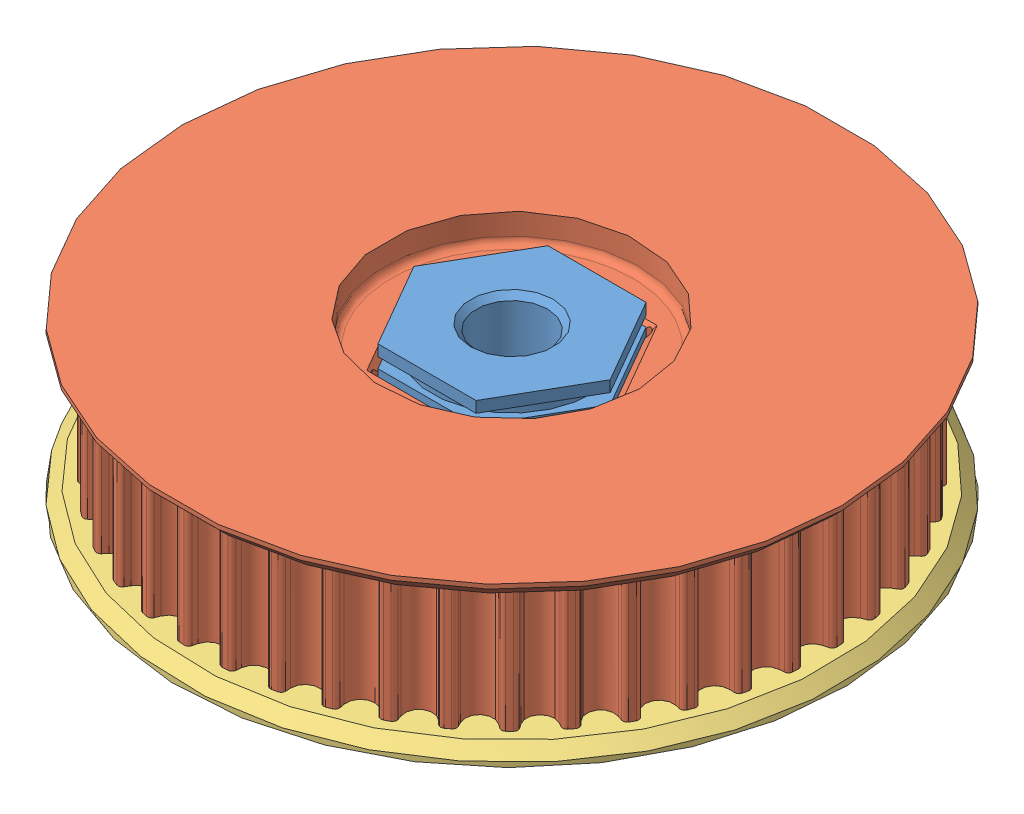
SolidWorks assembly _8MM_SHAFT_44T_HTD_PULLEY_ASM, configuration Default. Lengths in mm.
Overall size (100.97 27.3 100.97).
7 component instances, 5 part files, 0 mates.
Components (placement in the parent):
- 8MM_PULLEY_HUB-1: 8MM_PULLEY_HUB [Default] at origin size (22 26.54 19.05)
- HTD_TB_PULLEY_44T-1: HTD_TB_PULLEY_44T [Default] at (0 25.555 0) x (-1 0 0) z (0 -1 0) size (73.91 73.91 16.02)
- 44T_HTD_PULLEY_FLANGE-1: 44T_HTD_PULLEY_FLANGE [Default] at (0 9.5302 0) x (0.5 0 0.866025) z (-0.866025 0 0.5) size (73.91 1.75 73.91)
- 217-2736_20121205_ASM-1: 217-2736_20121205_ASM [Default] at (-4.5154 5.7531 -2.6156) x (-1 0 0) z (0 1 0) size (25.39 25.4 6.35)
  - 217-2736_20121205_1_ASM-1: 217-2736_20121205_1_ASM [Default] at origin size (25.39 25.4 6.35)
    - 217-2736-001_REV1-1-SOLID1-1: 217-2736-001_REV1-1-SOLID1 [Default] at origin size (25.39 25.4 6.35)
    - 92185A108-1-SOLID1-1: 92185A108-1-SOLID1 [Default] at origin size (4.65 12.51 4.65)
